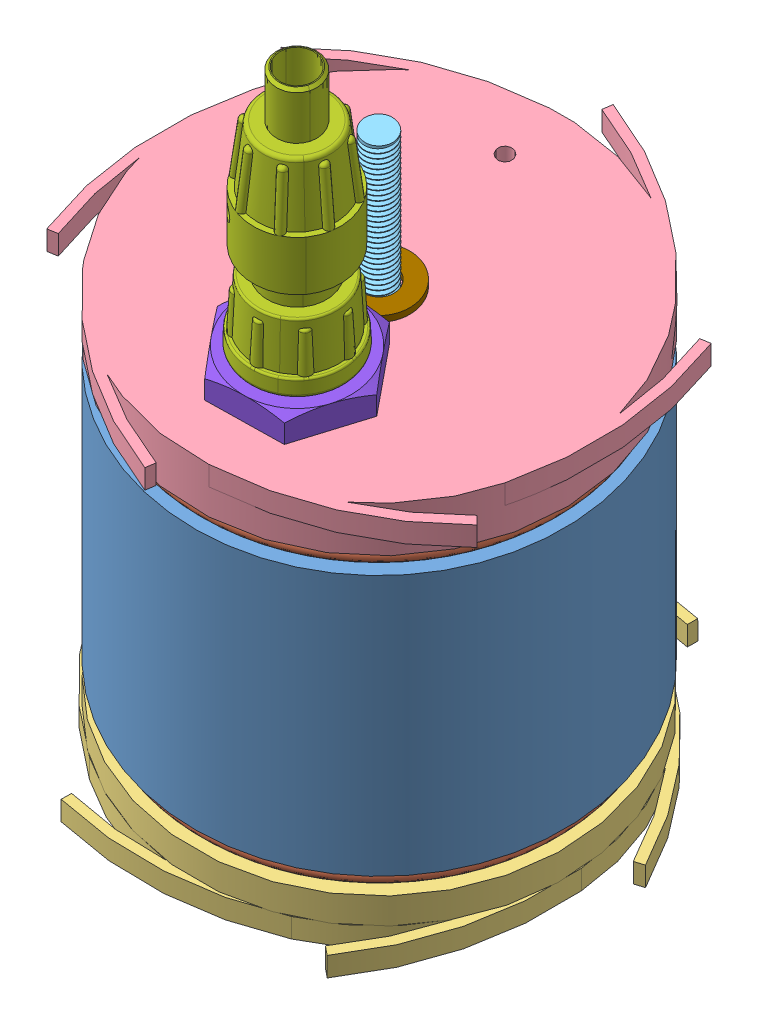
SolidWorks assembly PAB2, configuration Default. Lengths in mm.
Overall size (78.4 105.7 78.61).
10 component instances, 9 part files, 18 mates.
Components (placement in the parent):
- SMC5447T40111-1: SMC5447T40111 [Default] at (45.327 -14.7952 31.8539) x (0.989736 -0.142532 -0.010339) z (-0.010339 -0.14358 0.989585) size (54 40 54)
- 133 Buna-N O-Ring, 50A Durometer, Round-1: 133 Buna-N O-Ring, 50A Durometer, Round [Default] at (65.0494 -21.0197 45.6209) x (-0.802451 0.199254 -0.562469) z (0.142532 0.979321 0.14358) size (52.24 52.24 2.62)
- 133 Buna-N O-Ring, 50A Durometer, Round-2: 133 Buna-N O-Ring, 50A Durometer, Round [Default] at (71.6314 20.75 50.9985) x (-0.822922 0.197853 -0.532592) z (0.142532 0.979321 0.14358) size (52.24 52.24 2.62)
- PAB2_base_spring_bottom-1: PAB2_base_spring_bottom [Default] at (45.5243 -13.44 32.0526) x (0.988577 -0.148031 0.028325) z (-0.048994 -0.137902 0.989233) size (61.33 11 58.02)
- PAB2_base_spring_top-1: PAB2_base_spring_top [Default] at (50.8311 23.0225 37.3984) x (-0.163457 0.166358 -0.972423) z (-0.9762 0.115132 0.183788) size (61.33 11 58.02)
- long_screw-1: long_screw [Default] at (43.9564 -24.2125 30.4732) x (0.831636 -0.19715 0.519147) z (-0.536718 -0.045411 0.842538) size (8.08 80.01 7)
- 17282-2PG-300_Housing.step-1: 17282-2PG-300_Housing.step [Default] at (53.5446 24.9042 50.6329) x (-0.822922 0.197853 -0.532592) z (0.142532 0.979321 0.14358) size (15.88 15.88 21.29)
- 16282-2SG-3XX.step-1: 16282-2SG-3XX.step [Default] at (57.9239 54.9939 55.0444) x (-0.77827 0.200512 -0.595056) z (-0.142532 -0.979321 -0.14358) size (13.51 13.51 39.62)
- 17282-2PG-300_Nut.step-1: 17282-2PG-300_Nut.step [Default] at (53.9772 27.8763 51.0686) x (0.982235 -0.122059 -0.142532) z (0.142532 0.979321 0.14358) size (18.19 18.13 3.56)
- m4_washer-1: m4_washer [Default] at (52.3989 33.795 38.9778) x (0.989736 -0.142532 -0.010339) z (-0.010339 -0.14358 0.989585) size (9 0.9 9)
Mates (geometry in assembly coordinates):
- Tangent12: tangent anti-aligned: plane of SMC5447T40111-1 through (45.0293 -14.7184 31.6255) normal (-0.142532 -0.979321 -0.14358); torus of 133 Buna-N O-Ring, 50A Durometer, Round-1
- Coincident3: coincident aligned: plane of SMC5447T40111-1 through (50.7305 24.4545 37.3687) normal (0.142532 0.979321 0.14358); plane of 133 Buna-N O-Ring, 50A Durometer, Round-2 through (71.1472 19.5457 50.5823) normal (0.142532 0.979321 0.14358)
- Concentric3: concentric aligned: cylinder of SMC5447T40111-1 through (50.7305 24.4545 37.3687) axis (-0.142532 -0.979321 -0.14358) radius 23.5; line of 133 Buna-N O-Ring, 50A Durometer, Round-2 through (51.1221 27.1447 37.7631) axis (-0.142532 -0.979321 -0.14358)
- Tangent16: tangent anti-aligned: torus of 133 Buna-N O-Ring, 50A Durometer, Round-1; plane of PAB2_base_spring_bottom-1 through (18.2626 -13.3604 30.7135) normal (0.142532 0.979321 0.14358)
- Concentric4: concentric anti-aligned: line of 133 Buna-N O-Ring, 50A Durometer, Round-1 through (45.3457 -14.6671 31.8727) axis (-0.142532 -0.979321 -0.14358); cylinder of PAB2_base_spring_bottom-1 through (44.9541 -17.3573 31.4783) axis (0.142532 0.979321 0.14358) radius 2.1
- Tangent18: tangent anti-aligned: torus of 133 Buna-N O-Ring, 50A Durometer, Round-2; plane of PAB2_base_spring_top-1 through (55.5167 22.5249 63.9998) normal (-0.142532 -0.979321 -0.14358)
- Concentric6: concentric aligned: line of 133 Buna-N O-Ring, 50A Durometer, Round-2 through (51.1221 27.1447 37.7631) axis (-0.142532 -0.979321 -0.14358); cylinder of PAB2_base_spring_top-1 through (51.1034 27.0166 37.7443) axis (-0.142532 -0.979321 -0.14358) radius 2.1
- Coincident7: coincident aligned: plane of PAB2_base_spring_bottom-1 through (43.9564 -24.2125 30.4732) normal (-0.142532 -0.979321 -0.14358); plane of long_screw-1 through (43.6586 -24.1357 30.2448) normal (-0.142532 -0.979321 -0.14358)
- Coincident11: coincident anti-aligned: plane of PAB2_base_spring_top-1 through (53.6559 27.7919 50.8166) normal (-0.142532 -0.979321 -0.14358); plane of 17282-2PG-300_Housing.step-1 through (53.6559 27.7919 50.8166) normal (0.142532 0.979321 0.14358)
- Concentric11: concentric aligned: cylinder of PAB2_base_spring_top-1 through (52.8007 21.916 49.9551) axis (0.142532 0.979321 0.14358) radius 5.7; cylinder of 17282-2PG-300_Housing.step-1 through (54.2533 31.8962 51.4183) axis (0.142532 0.979321 0.14358) radius 3.6322
- Coincident12: coincident anti-aligned: plane of PAB2_base_spring_top-1 through (52.1011 33.8718 38.7494) normal (0.142532 0.979321 0.14358); plane of 17282-2PG-300_Nut.step-1 through (56.1482 29.1683 66.8132) normal (-0.142532 -0.979321 -0.14358)
- Concentric12: concentric anti-aligned: circle of 17282-2PG-300_Housing.step-1; circle of 17282-2PG-300_Nut.step-1
- Coincident13: coincident anti-aligned: plane of 17282-2PG-300_Housing.step-1 through (52.8172 32.5643 53.8854) normal (0.142532 0.979321 0.14358); plane of 16282-2SG-3XX.step-1 through (54.3679 32.6834 51.5337) normal (-0.142532 -0.979321 -0.14358)
- Concentric13: concentric aligned: cylinder of 17282-2PG-300_Housing.step-1 through (54.2533 31.8962 51.4183) axis (0.142532 0.979321 0.14358) radius 3.6322; cylinder of 16282-2SG-3XX.step-1 through (54.3679 32.6834 51.5337) axis (0.142532 0.979321 0.14358) radius 3.4544
- Concentric14: concentric anti-aligned: cylinder of PAB2_base_spring_top-1 through (51.1034 27.0166 37.7443) axis (-0.142532 -0.979321 -0.14358) radius 2.1; circle of long_screw-1
- Concentric15: concentric anti-aligned: circle of PAB2_base_spring_top-1; circle of m4_washer-1
- Coincident15: coincident anti-aligned: plane of PAB2_base_spring_top-1 through (52.1011 33.8718 38.7494) normal (0.142532 0.979321 0.14358); plane of m4_washer-1 through (52.1011 33.8718 38.7494) normal (-0.142532 -0.979321 -0.14358)
- Concentric16: concentric aligned: circle of PAB2_base_spring_bottom-1; circle of long_screw-1
